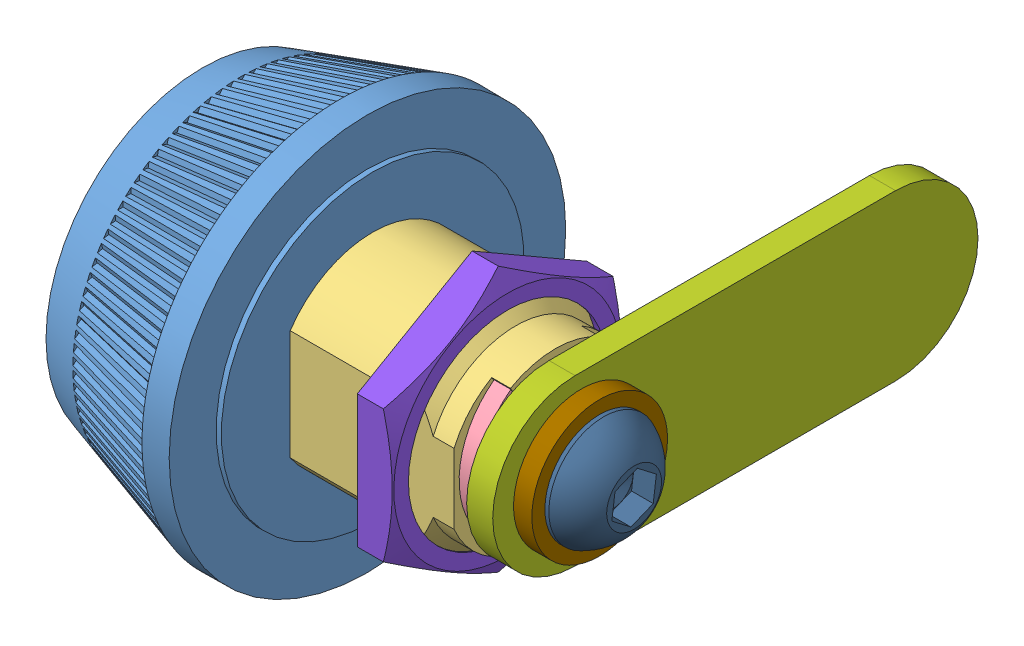
SolidWorks assembly CC-7850-virtual, configuration Default. Lengths in mm.
Overall size (43.62 38 57).
13 component instances, 10 part files, 0 mates.
Components (placement in the parent):
- Copy of Cylinder-1.1_1^CC-7850-virtual-1: Copy of Cylinder-1.1_1^CC-7850-virtual [Default] at origin size (16.3 38 38) (virtual)
- Copy of Needle-1_1^CC-7850-virtual-1: Copy of Needle-1_1^CC-7850-virtual [Default] at (-10.3 5.1 0) x (0 1 0) z (1 0 0) size (3.1 15.23 15.24) (virtual)
- Copy of Needle-1_1^CC-7850-virtual-2: Copy of Needle-1_1^CC-7850-virtual [Default] at (-10.3 -1.9 0) x (0 1 0) z (1 0 0) size (3.1 15.23 15.24) (virtual)
- Copy of Needle-1_1^CC-7850-virtual-3: Copy of Needle-1_1^CC-7850-virtual [Default] at (-10.3 -8.9 0) x (0 1 0) z (1 0 0) size (3.1 15.23 15.24) (virtual)
- Copy of Rear-1.1_1^CC-7850-virtual-1: Copy of Rear-1.1_1^CC-7850-virtual [Default] at (-2.3 0 0) size (17.5 19 15.8) (virtual)
- Copy of Cam-1.1_1^CC-7850-virtual-1: Copy of Cam-1.1_1^CC-7850-virtual [Default] at (16.7 0 0) x (0 0 1) z (1 0 0) size (15 15 1.6) (virtual)
- Copy of Bolt-1.1^CC-7850-virtual-1: Copy of Bolt-1.1^CC-7850-virtual [Default] at (-8.4 0 0) size (16.1 9.4 9.4) (virtual)
  - Copy of Bolt-1.1_1_2^Copy of Bolt-1.1_CC-7850-virtual-1: Copy of Bolt-1.1_1_2^Copy of Bolt-1.1_CC-7850-virtual [Default] at origin size (1.25 7 5.4) (virtual)
  - Copy of Bolt-1.1_1^Copy of Bolt-1.1_CC-7850-virtual-1: Copy of Bolt-1.1_1^Copy of Bolt-1.1_CC-7850-virtual [Default] at origin size (15.1 9.4 9.4) (virtual)
- Copy of Cam-Plate-1.1_1^CC-7850-virtual-1: Copy of Cam-Plate-1.1_1^CC-7850-virtual [Default] at (17.5 0 0) x (0 -1 0) z (1 0 0) size (15.8 46.5 2.5) (virtual)
- Copy of Nut-1.1_1^CC-7850-virtual-1: Copy of Nut-1.1_1^CC-7850-virtual [Default] at (11.225 0 0) x (0 0 1) z (-1 0 0) size (22 25.4 3.4) (virtual)
- Copy of flat washer narrow_am_B18.22M - Plain washer, 6 mm, narrow^CC-7850-virtual-1: Copy of flat washer narrow_am_B18.22M - Plain washer, 6 mm, narrow^CC-7850-virtual [Default] at (20 0 0) x (-1 0 0) z (0 -0.666948 -0.745104) size (1.75 13 13) (virtual)
- Copy of socket button head cap screw_am_B18.3.4M - 6 x 1.0 x 6 SBHCS --N^CC-7850-virtual-1: Copy of socket button head cap screw_am_B18.3.4M - 6 x 1.0 x 6 SBHCS --N^CC-7850-virtual [Default] at (25.05 0 0) x (-1 0 0) z (0 0.924225 0.381849) size (9.95 10.61 10.56) (virtual)
